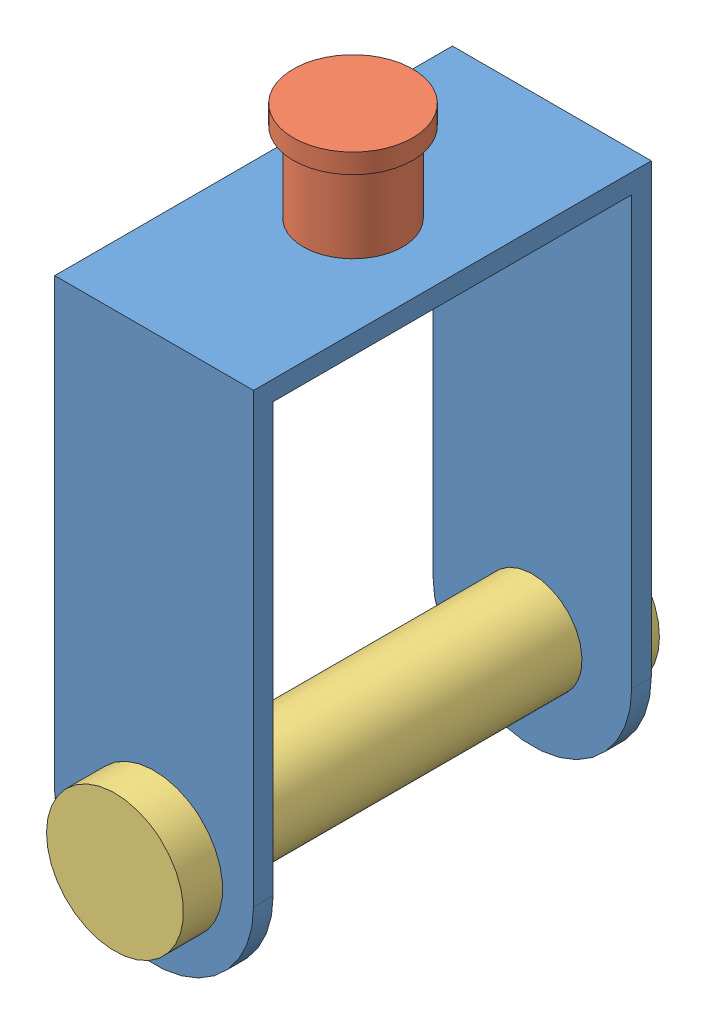
SolidWorks assembly Assem1, configuration Default. Lengths in mm.
Overall size (50.8 165.1 121.6).
3 component instances, 3 part files, 6 mates.
Components (placement in the parent):
- 1-1: 1 [Default] at (49.2145 66.9511 76.4655) size (50.8 139.7 101.6)
- wheelhinge-1: wheelhinge [Default] at (49.2145 188.9511 76.4655) x (0.436076 0 -0.89991) z (0.89991 0 0.436076) size (30.48 35.4 30.48)
- tyrepin-1: tyrepin [Default] at (49.2145 66.9511 76.4655) x (0.587335 0.809344 0) z (0 0 1) size (35 35 121.6)
Mates (geometry in assembly coordinates):
- Coincident2: coincident anti-aligned: plane of 1-1 through (-26.9855 176.2511 122.2655) normal (0 -1 0); plane of wheelhinge-1 through (49.2145 176.2511 76.4655) normal (0 1 0)
- Coincident7: coincident aligned: plane of 1-1 through (49.2145 66.9511 127.2655) normal (0 0 1); circle of tyrepin-1
- Parallel1: parallel anti-aligned: cylinder of 1-1 through (49.2145 79.6511 76.4655) axis (0 1 0) radius 12.7; cylinder of wheelhinge-1 through (49.2145 201.6511 76.4655) axis (0 -1 0) radius 12.7
- Concentric1: concentric anti-aligned: cylinder of 1-1 through (49.2145 79.6511 76.4655) axis (0 1 0) radius 12.7; cylinder of wheelhinge-1 through (49.2145 201.6511 76.4655) axis (0 -1 0) radius 12.7
- Concentric2: concentric aligned: cylinder of 1-1 through (49.2145 66.9511 127.2655) axis (0 0 -1) radius 12.7; cylinder of tyrepin-1 through (49.2145 66.9511 127.2655) axis (0 0 -1) radius 12.7
- Lock1: lock: unknown of 1-1; unknown of tyrepin-1
